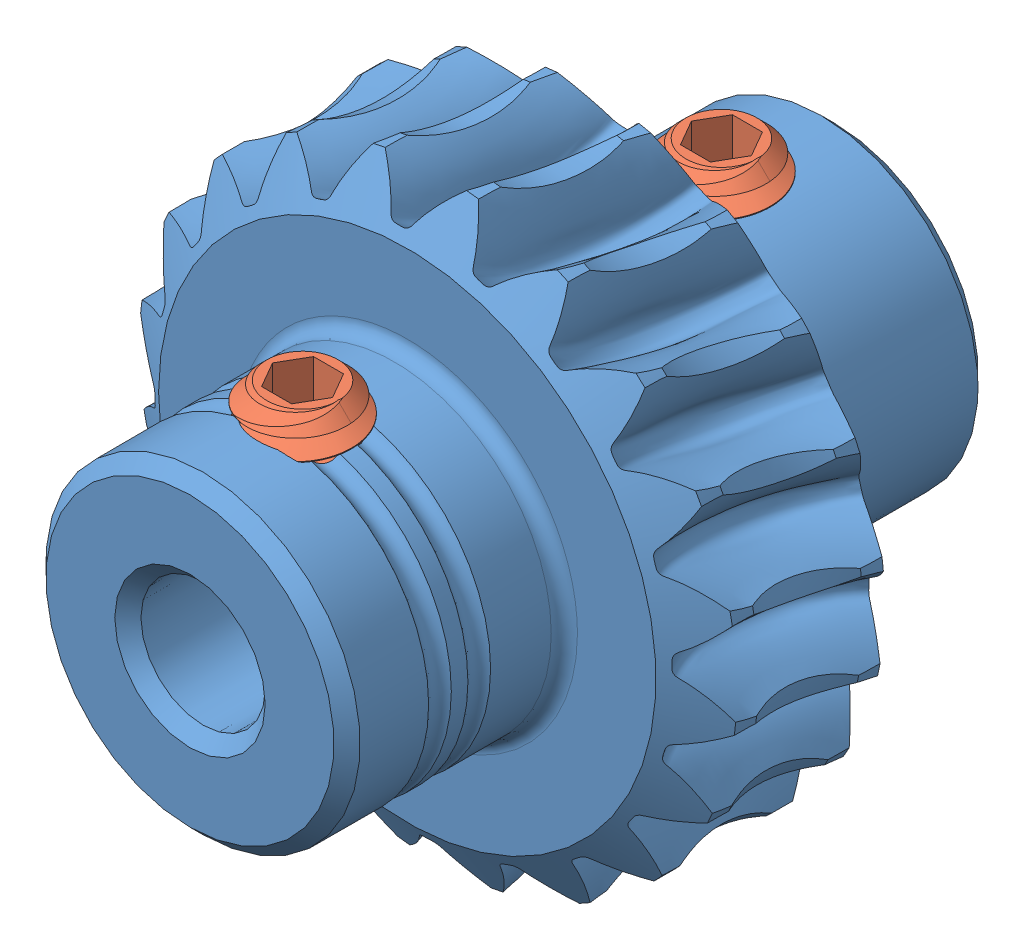
SolidWorks assembly Tetrix Worm Gear (10 to 1), configuration Default. Lengths in mm.
Overall size (23.94 23.94 24.6).
3 component instances, 2 part files, 0 mates.
Components (placement in the parent):
- Tetrix Worm Gear (10 to 1) Body-1: Tetrix Worm Gear (10 to 1) Body [Default] at origin size (23.94 23.94 24.6)
- Tetrix Worm Gear (10 to 1) Set Screw-1: Tetrix Worm Gear (10 to 1) Set Screw [Default] at (0 2.375 8) x (0 0 1) z (-1 0 0) size (4.02 4.91 3.99)
- Tetrix Worm Gear (10 to 1) Set Screw-2: Tetrix Worm Gear (10 to 1) Set Screw [Default] at (0 2.375 -8) x (0 0 1) z (-1 0 0) size (4.02 4.91 3.99)
